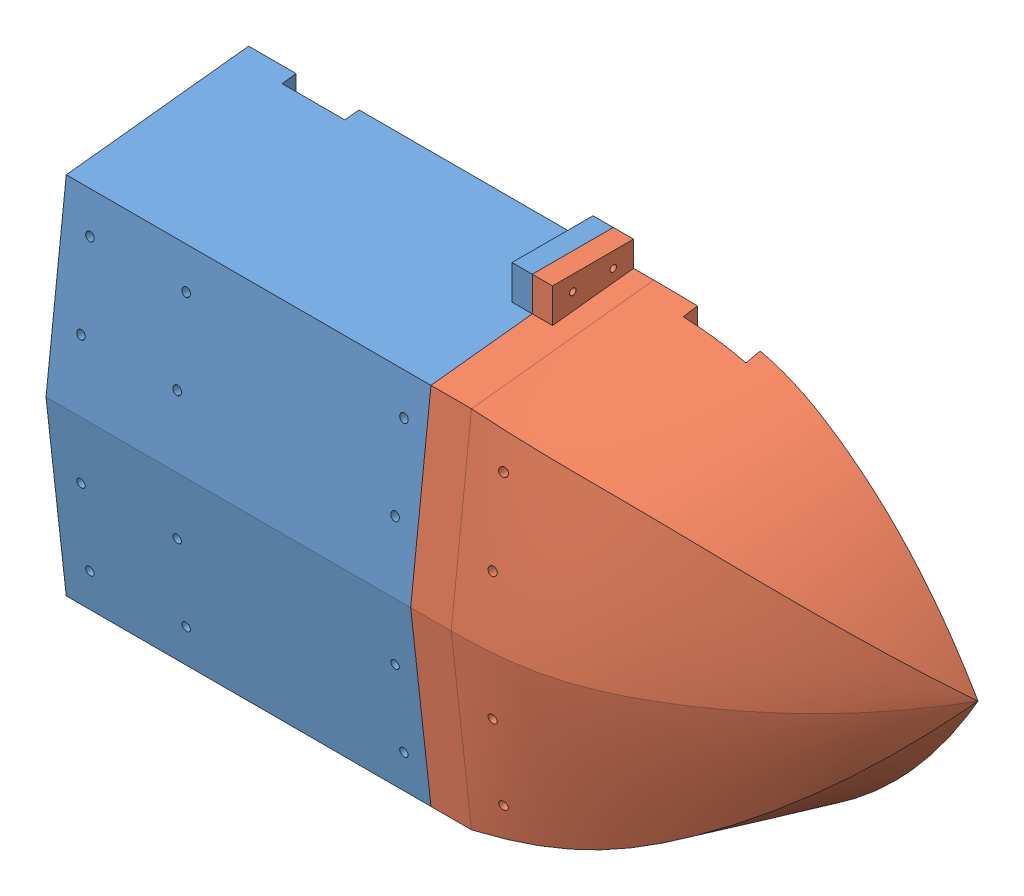
SolidWorks assembly Coque_assembly_v2, configuration Défaut. Lengths in mm.
Overall size (370 225 100.01).
4 component instances, 4 part files, 9 mates.
Components (placement in the parent):
- Coque_arriere_v2-1: Coque_arriere_v2 [Défaut] at origin size (180 225 100)
- Coque_avant_v2-1: Coque_avant_v2 [Défaut] at (190 0 0) size (190.01 225 100.01)
- WheelHolder_arriere-1: WheelHolder_arriere [Défaut] at (27.5 0 9.4969) x (0 -1 0) z (0 0 1) size (200 55 70) (hidden)
- WheelHolder_avant-1: WheelHolder_avant [Défaut] at (182.5 0 10) x (0 1 0) z (0 0 1) size (200 55.55 71.52) (hidden)
Mates (geometry in assembly coordinates):
- Coincident1: coordinate: point of Coque_arriere_v2-1
- Coincident2: coincident anti-aligned: line of Coque_arriere_v2-1 through (170 95.5556 -60) axis (0 -0.110432 0.993884); line of Coque_avant_v2-1 through (170 90 -10) axis (0 0.110432 -0.993884)
- Coincident3: coincident anti-aligned: line of Coque_arriere_v2-1 through (170 90 -10) axis (0 -0.993884 0.110432); line of Coque_avant_v2-1 through (170 0 0) axis (0 0.993884 -0.110432)
- Coincident6: coincident aligned: line of Coque_arriere_v2-1 through (0 180 -10) axis (0 0 1); line of WheelHolder_arriere-1 through (55 0 0) axis (0 1 0)
- Distance1: distance = 10 mm aligned: plane of Coque_arriere_v2-1 through (-10 0 0) normal (-1 0 0); plane of WheelHolder_arriere-1 through (0 100 -48.0031) normal (-1 0 0)
- Parallel2: parallel aligned: plane of Coque_arriere_v2-1 through (-10 100 -100) normal (0 0 -1); plane of WheelHolder_arriere-1 through (27.5 0 -48.0031) normal (0 0 -1)
- Distance2: distance = 100 mm anti-aligned: plane of WheelHolder_avant-1 through (155 -100 -47.5) normal (-1 0 0); plane of WheelHolder_arriere-1 through (55 100 -48.0031) normal (1 0 0)
- Coincident10: coincident aligned: line of Coque_arriere_v2-1 through (0 180 -10) axis (0 0 1); line of WheelHolder_avant-1 through (155 0 0) axis (1 0 0)
- Parallel3: parallel aligned: plane of Coque_avant_v2-1 through (190 0 -100) normal (0 0 -1); plane of WheelHolder_avant-1 through (182.5 0 -47.5) normal (0 0 -1)
